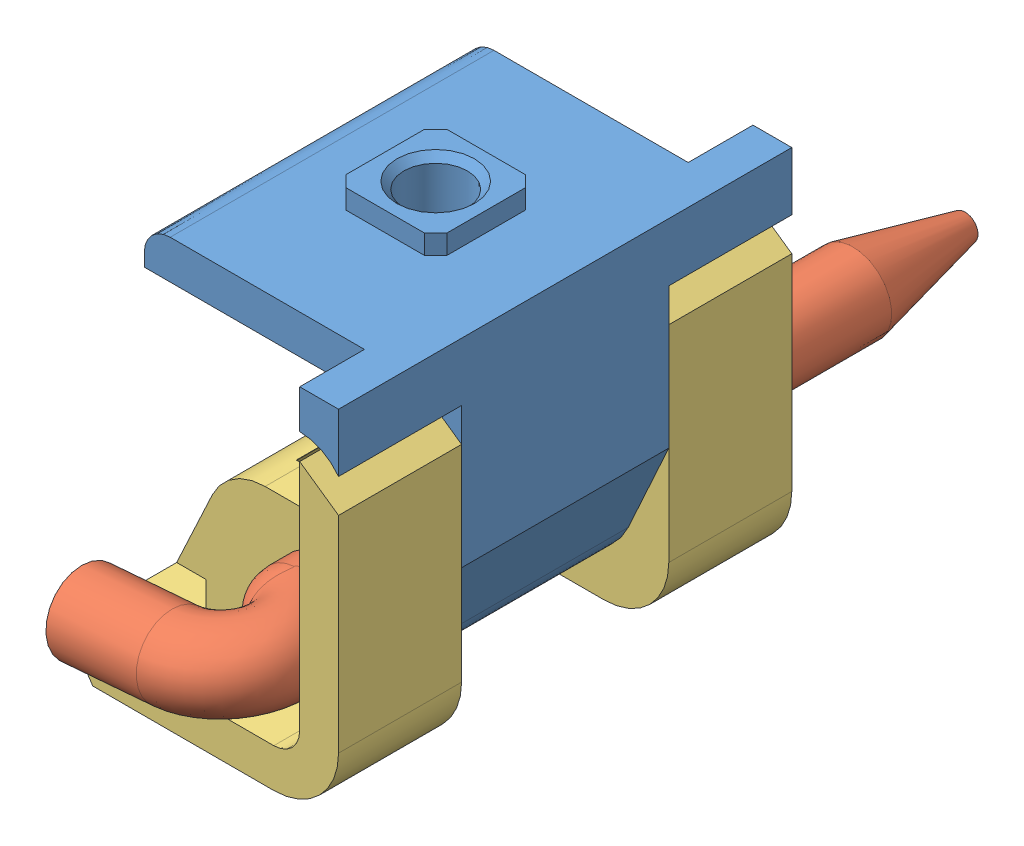
SolidWorks assembly CH04568150PCL, configuration Défaut. Lengths in mm.
Overall size (21 29.5 62).
3 component instances, 3 part files, 4 mates.
Components (placement in the parent):
- CH04568150PCLP1-1: CH04568150PCLP1 [Défaut] at (-11.2039 17.4438 0) size (20 26.85 35)
- CH04568150PCLP3-1: CH04568150PCLP3 [Défaut] at (-12.9368 17.2115 -0.8805) x (0.996722 0.080906 0) z (0 0 1) size (14 6.01 62)
- CH04568150PCLP2-1: CH04568150PCLP2 [Défaut] at (-11.2039 17.4438 0) size (21 23 35)
Mates (geometry in assembly coordinates):
- Coïncidente1: coincident anti-aligned: plane of CH04568150PCLP1-1 through (-8.2557 4.1241 -8) normal (0 0 -1); plane of CH04568150PCLP2-1 through (-7.5682 -2.2809 -8) normal (0 0 1)
- Coaxiale1: concentric aligned: cylinder of CH04568150PCLP1-1 through (-9.2039 -4.0562 0) axis (0 0 1) radius 3; cylinder of CH04568150PCLP2-1 through (-9.2039 -4.0562 0) axis (0 0 1) radius 3
- Coaxiale2: concentric anti-aligned: cylinder of CH04568150PCLP1-1 through (-9.2039 -4.0562 0) axis (0 0 1) radius 3; cylinder of CH04568150PCLP3-1 through (-9.2039 -4.0562 0.4195) axis (0 0 -1) radius 3
- Coïncidente3: coincident aligned: plane of CH04568150PCLP1-1 through (-1.2039 6.0185 -8) normal (1 0 0); plane of CH04568150PCLP2-1 through (-1.2039 0.8935 -17.5) normal (1 0 0)
